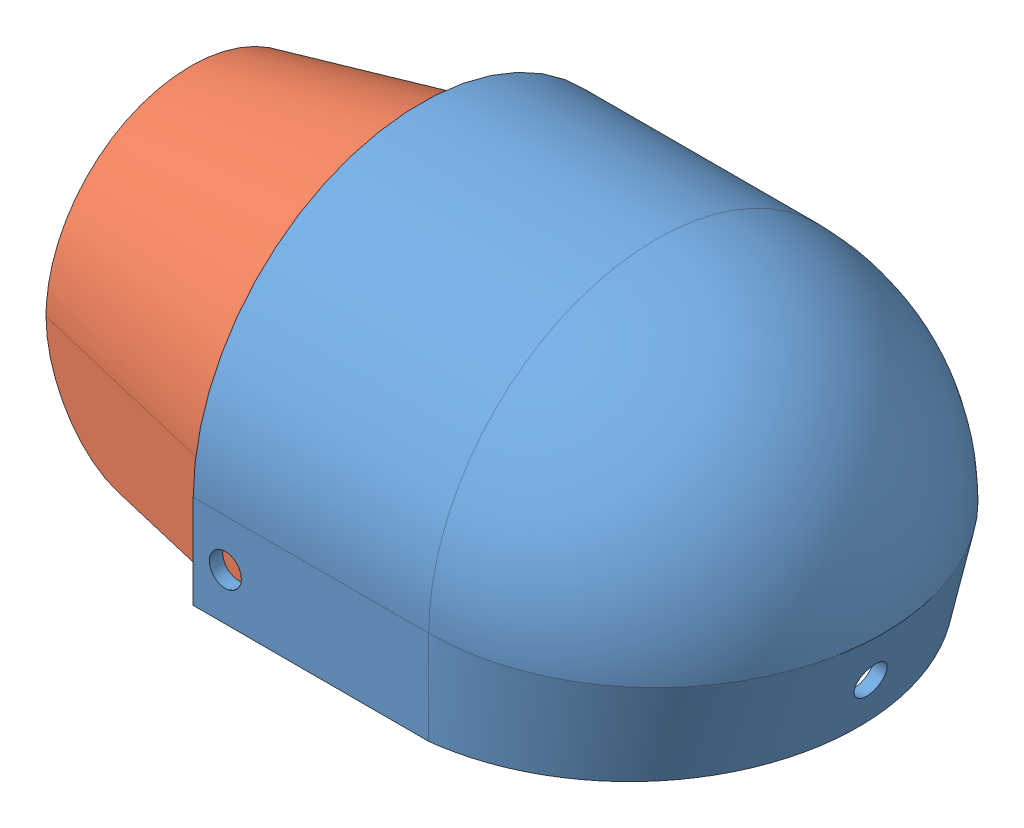
SolidWorks assembly Body, configuration Default. Lengths in mm.
Overall size (259.01 120 170.02).
2 component instances, 2 part files, 2 mates.
Components (placement in the parent):
- Back Shell-1: Back Shell [Default] at (10.2877 132.559 137.9644) size (209.01 120 170.02)
- Front Shell-1: Front Shell [Default] at (20.2877 132.559 137.9644) size (180 115 160)
Mates (geometry in assembly coordinates):
- Concentric3: concentric aligned: circle of Back Shell-1; circle of Front Shell-1
- Tangent4: tangent: cylinder of Back Shell-1 through (-1.7123 115.059 237.9644) axis (0 0 -1) radius 6; curve of Front Shell-1
